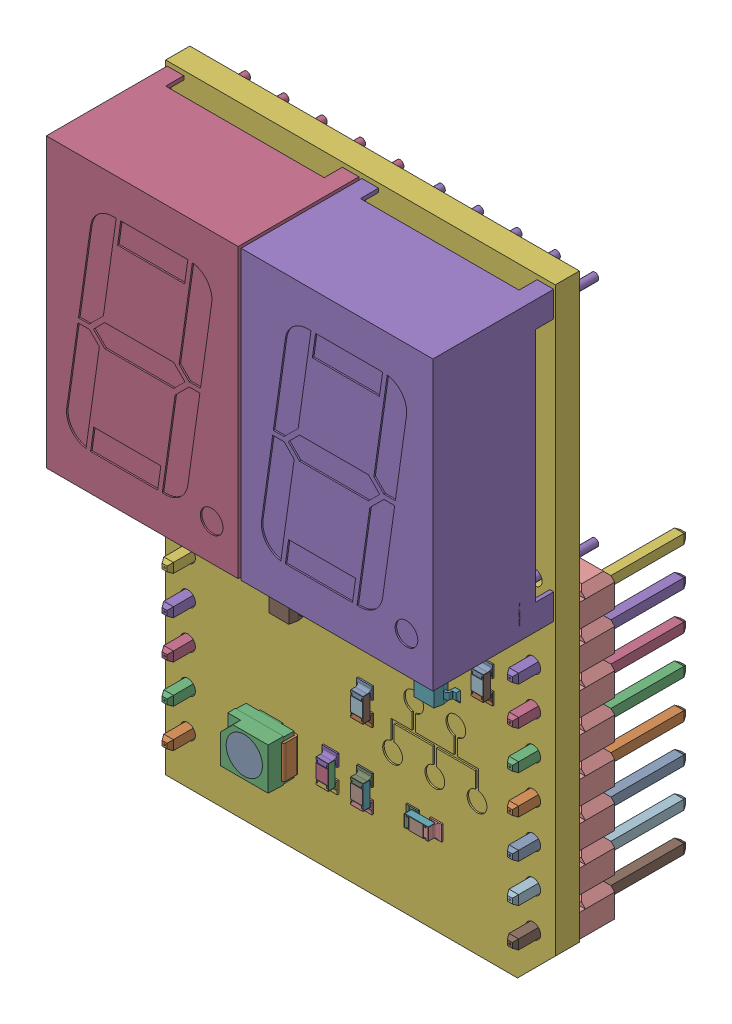
SolidWorks assembly 7_Seg_Click_Board, configuration Default. Lengths in mm.
Overall size (25.8 41 17.94).
119 component instances, 16 part files, 0 mates.
Components (placement in the parent):
- m20-9770842_asm.stp.1-1: m20-9770842_asm.stp.1 [Default] at (77.5496 46.3595 4.37) x (0 1 0) z (-1 0 0) size (20.32 11.48 2.54)
  - M20-977_ASM-1: M20-977_ASM [Default] at origin size (20.32 11.48 2.54)
    - M20-977-MOULD_2-1: M20-977-MOULD_2 [Default] at origin size (20.32 2.54 2.54)
    - M20-977-PIN.7-1: M20-977-PIN.7 [Default] at (2.54 -5.68 0) x (1 0 0) z (0 0 -1) size (0.64 11.48 0.64)
    - M20-977-PIN.7-2: M20-977-PIN.7 [Default] at (5.08 -5.68 0) x (1 0 0) z (0 0 -1) size (0.64 11.48 0.64)
    - M20-977-PIN.7-3: M20-977-PIN.7 [Default] at (7.62 -5.68 0) x (1 0 0) z (0 0 -1) size (0.64 11.48 0.64)
    - M20-977-PIN.7-4: M20-977-PIN.7 [Default] at (10.16 -5.68 0) x (1 0 0) z (0 0 -1) size (0.64 11.48 0.64)
    - M20-977-PIN.7-5: M20-977-PIN.7 [Default] at (12.7 -5.68 0) x (1 0 0) z (0 0 -1) size (0.64 11.48 0.64)
    - M20-977-PIN.7-6: M20-977-PIN.7 [Default] at (15.24 -5.68 0) x (1 0 0) z (0 0 -1) size (0.64 11.48 0.64)
    - M20-977-PIN.7-7: M20-977-PIN.7 [Default] at (17.78 -5.68 0) x (1 0 0) z (0 0 -1) size (0.64 11.48 0.64)
    - M20-977-PIN.7-8: M20-977-PIN.7 [Default] at (20.32 -5.68 0) x (1 0 0) z (0 0 -1) size (0.64 11.48 0.64)
- m20-9770842_asm.stp-1: m20-9770842_asm.stp [Default] at (100.4096 46.3595 4.37) x (0 1 0) z (-1 0 0) size (20.32 11.48 2.54)
  - M20-977_ASM_2-1: M20-977_ASM_2 [Default] at origin size (20.32 11.48 2.54)
    - M20-977-MOULD-1: M20-977-MOULD [Default] at origin size (20.32 2.54 2.54)
    - M20-977-PIN.5-1: M20-977-PIN.5 [Default] at (2.54 -5.68 0) x (1 0 0) z (0 0 -1) size (0.64 11.48 0.64)
    - M20-977-PIN.5-2: M20-977-PIN.5 [Default] at (5.08 -5.68 0) x (1 0 0) z (0 0 -1) size (0.64 11.48 0.64)
    - M20-977-PIN.5-3: M20-977-PIN.5 [Default] at (7.62 -5.68 0) x (1 0 0) z (0 0 -1) size (0.64 11.48 0.64)
    - M20-977-PIN.5-4: M20-977-PIN.5 [Default] at (10.16 -5.68 0) x (1 0 0) z (0 0 -1) size (0.64 11.48 0.64)
    - M20-977-PIN.5-5: M20-977-PIN.5 [Default] at (12.7 -5.68 0) x (1 0 0) z (0 0 -1) size (0.64 11.48 0.64)
    - M20-977-PIN.5-6: M20-977-PIN.5 [Default] at (15.24 -5.68 0) x (1 0 0) z (0 0 -1) size (0.64 11.48 0.64)
    - M20-977-PIN.5-7: M20-977-PIN.5 [Default] at (17.78 -5.68 0) x (1 0 0) z (0 0 -1) size (0.64 11.48 0.64)
    - M20-977-PIN.5-8: M20-977-PIN.5 [Default] at (20.32 -5.68 0) x (1 0 0) z (0 0 -1) size (0.64 11.48 0.64)
- arduino_uno_MLC0603.1.1.8-1: arduino_uno_MLC0603.1.1.8 [Default] at (93.2677 51.543 8.51) x (1 0 0) z (0 -1 0) size (2.36 0.6 1.03)
  - p4-1: p4 [Default] at origin size (1.55 0.45 0.8)
  - p3-1: p3 [Default] at origin size (1 0.03 0.8)
  - p2-1: p2 [Default] at origin size (0.8 0.6 1.03)
  - p1-1: p1 [Default] at origin size (0.8 0.6 1.03)
- User_Library-arduino_uno_ssot3.1.1-1: User_Library-arduino_uno_ssot3.1.1 [Default] at (84.6189 60.8527 8.41) x (0 1 0) z (1 0 0) size (3 1.13 3.09)
- Everlight_67-21SRC-TR8.STEP-1: Everlight_67-21SRC-TR8.STEP [Default] at (83.1478 51.2463 8.51) x (0 -1 0) z (-1 0 0) size (2.8 1.86 3.5)
  - User_Library-Everlight_67-21SRC-TR8-1: User_Library-Everlight_67-21SRC-TR8 [Default] at origin size (2.8 1.86 3.5)
    - User_Library-Everlight_67-21SRC-TR8_Imported_3-1: User_Library-Everlight_67-21SRC-TR8_Imported_3 [Default] at origin size (0.48 0.2 0.48)
    - User_Library-Everlight_67-21SRC-TR8_Imported_4-1: User_Library-Everlight_67-21SRC-TR8_Imported_4 [Default] at origin size (2.4 0.85 2.4)
    - User_Library-Everlight_67-21SRC-TR8_Imported-1: User_Library-Everlight_67-21SRC-TR8_Imported [Default] at origin size (2.2 1.01 3.5)
    - User_Library-Everlight_67-21SRC-TR8_Imported_2-1: User_Library-Everlight_67-21SRC-TR8_Imported_2 [Default] at origin size (2.8 1.8 3.2)
- Disp_SA56-11.1-1: Disp_SA56-11.1 [Default] at (77.4495 69.2194 8.4773) size (12.7 19.05 12)
  - SW3dPS-Disp_SA56-11-1: SW3dPS-Disp_SA56-11 [Default] at origin size (12.7 19.05 12)
    - SW3dPS-Disp_SA56-11_Open_CASCADE_STEP_translator_6.2_78.2-1: SW3dPS-Disp_SA56-11_Open_CASCADE_STEP_translator_6.2_78.2 [Default] at origin size (12.7 19.05 12)
      - SW3dPS-Disp_SA56-11_Disp_SA56-12_2-1: SW3dPS-Disp_SA56-11_Disp_SA56-12_2 [Default] at (5.0801 7.6201 8.0327) x (1 0 0) z (0 -1 0) size (12.7 12 19.05)
- Disp_SA56-11-1: Disp_SA56-11 [Default] at (90.3495 69.2194 8.4773) size (12.7 19.05 12)
  - SW3dPS-Disp_SA56-11_2-1: SW3dPS-Disp_SA56-11_2 [Default] at origin size (12.7 19.05 12)
    - SW3dPS-Disp_SA56-11_Open_CASCADE_STEP_translator_6.2_78.2_2-1: SW3dPS-Disp_SA56-11_Open_CASCADE_STEP_translator_6.2_78.2_2 [Default] at origin size (12.7 19.05 12)
      - SW3dPS-Disp_SA56-11_Disp_SA56-12-1: SW3dPS-Disp_SA56-11_Disp_SA56-12 [Default] at (5.0801 7.6201 8.0327) x (1 0 0) z (0 -1 0) size (12.7 12 19.05)
- 7_Seg_Click_Board-1: 7_Seg_Click_Board [Default] at (0 0.5 0) size (25.8 41 1.6)
- arduino_uno_MLC0603.1.1.8-2: arduino_uno_MLC0603.1.1.8 [Default] at (97.3056 65.7088 8.51) x (0 -1 0) z (-1 0 0) size (2.36 0.6 1.03)
  - p4-1: p4 [Default] at origin size (1.55 0.45 0.8)
  - p3-1: p3 [Default] at origin size (1 0.03 0.8)
  - p2-1: p2 [Default] at origin size (0.8 0.6 1.03)
  - p1-1: p1 [Default] at origin size (0.8 0.6 1.03)
- arduino_uno_MLC0603.1.1.8-3: arduino_uno_MLC0603.1.1.8 [Default] at (97.3056 61.7088 8.51) x (0 -1 0) z (-1 0 0) size (2.36 0.6 1.03)
  - p4-1: p4 [Default] at origin size (1.55 0.45 0.8)
  - p3-1: p3 [Default] at origin size (1 0.03 0.8)
  - p2-1: p2 [Default] at origin size (0.8 0.6 1.03)
  - p1-1: p1 [Default] at origin size (0.8 0.6 1.03)
- arduino_uno_MLC0603.1.1.8-4: arduino_uno_MLC0603.1.1.8 [Default] at (95.0056 65.7088 8.51) x (0 -1 0) z (-1 0 0) size (2.36 0.6 1.03)
  - p4-1: p4 [Default] at origin size (1.55 0.45 0.8)
  - p3-1: p3 [Default] at origin size (1 0.03 0.8)
  - p2-1: p2 [Default] at origin size (0.8 0.6 1.03)
  - p1-1: p1 [Default] at origin size (0.8 0.6 1.03)
- arduino_uno_MLC0603.1.1.8-5: arduino_uno_MLC0603.1.1.8 [Default] at (92.7056 65.7088 8.51) x (0 -1 0) z (-1 0 0) size (2.36 0.6 1.03)
  - p4-1: p4 [Default] at origin size (1.55 0.45 0.8)
  - p3-1: p3 [Default] at origin size (1 0.03 0.8)
  - p2-1: p2 [Default] at origin size (0.8 0.6 1.03)
  - p1-1: p1 [Default] at origin size (0.8 0.6 1.03)
- arduino_uno_MLC0603.1.1.8-6: arduino_uno_MLC0603.1.1.8 [Default] at (90.4056 65.7088 8.51) x (0 -1 0) z (-1 0 0) size (2.36 0.6 1.03)
  - p4-1: p4 [Default] at origin size (1.55 0.45 0.8)
  - p3-1: p3 [Default] at origin size (1 0.03 0.8)
  - p2-1: p2 [Default] at origin size (0.8 0.6 1.03)
  - p1-1: p1 [Default] at origin size (0.8 0.6 1.03)
- arduino_uno_MLC0603.1.1.8-7: arduino_uno_MLC0603.1.1.8 [Default] at (90.4056 61.7088 8.51) x (0 -1 0) z (-1 0 0) size (2.36 0.6 1.03)
  - p4-1: p4 [Default] at origin size (1.55 0.45 0.8)
  - p3-1: p3 [Default] at origin size (1 0.03 0.8)
  - p2-1: p2 [Default] at origin size (0.8 0.6 1.03)
  - p1-1: p1 [Default] at origin size (0.8 0.6 1.03)
- arduino_uno_MLC0603.1.1.8-8: arduino_uno_MLC0603.1.1.8 [Default] at (88.1056 65.7088 8.51) x (0 -1 0) z (-1 0 0) size (2.36 0.6 1.03)
  - p4-1: p4 [Default] at origin size (1.55 0.45 0.8)
  - p3-1: p3 [Default] at origin size (1 0.03 0.8)
  - p2-1: p2 [Default] at origin size (0.8 0.6 1.03)
  - p1-1: p1 [Default] at origin size (0.8 0.6 1.03)
- arduino_uno_MLC0603.1.1.8-9: arduino_uno_MLC0603.1.1.8 [Default] at (88.1056 61.7088 8.51) x (0 -1 0) z (-1 0 0) size (2.36 0.6 1.03)
  - p4-1: p4 [Default] at origin size (1.55 0.45 0.8)
  - p3-1: p3 [Default] at origin size (1 0.03 0.8)
  - p2-1: p2 [Default] at origin size (0.8 0.6 1.03)
  - p1-1: p1 [Default] at origin size (0.8 0.6 1.03)
- arduino_uno_MLC0603.1.1.8-10: arduino_uno_MLC0603.1.1.8 [Default] at (85.8056 65.7088 8.51) x (0 -1 0) z (-1 0 0) size (2.36 0.6 1.03)
  - p4-1: p4 [Default] at origin size (1.55 0.45 0.8)
  - p3-1: p3 [Default] at origin size (1 0.03 0.8)
  - p2-1: p2 [Default] at origin size (0.8 0.6 1.03)
  - p1-1: p1 [Default] at origin size (0.8 0.6 1.03)
- arduino_uno_MLC0603.1.1.8-11: arduino_uno_MLC0603.1.1.8 [Default] at (83.5056 65.7088 8.51) x (0 -1 0) z (-1 0 0) size (2.36 0.6 1.03)
  - p4-1: p4 [Default] at origin size (1.55 0.45 0.8)
  - p3-1: p3 [Default] at origin size (1 0.03 0.8)
  - p2-1: p2 [Default] at origin size (0.8 0.6 1.03)
  - p1-1: p1 [Default] at origin size (0.8 0.6 1.03)
- arduino_uno_MLC0603.1.1.8-12: arduino_uno_MLC0603.1.1.8 [Default] at (81.2056 65.7088 8.51) x (0 -1 0) z (-1 0 0) size (2.36 0.6 1.03)
  - p4-1: p4 [Default] at origin size (1.55 0.45 0.8)
  - p3-1: p3 [Default] at origin size (1 0.03 0.8)
  - p2-1: p2 [Default] at origin size (0.8 0.6 1.03)
  - p1-1: p1 [Default] at origin size (0.8 0.6 1.03)
- arduino_uno_MLC0603.1.1.8-13: arduino_uno_MLC0603.1.1.8 [Default] at (81.2056 61.7088 8.51) x (0 -1 0) z (-1 0 0) size (2.36 0.6 1.03)
  - p4-1: p4 [Default] at origin size (1.55 0.45 0.8)
  - p3-1: p3 [Default] at origin size (1 0.03 0.8)
  - p2-1: p2 [Default] at origin size (0.8 0.6 1.03)
  - p1-1: p1 [Default] at origin size (0.8 0.6 1.03)
- arduino_uno_MLC0603.1.1.8-14: arduino_uno_MLC0603.1.1.8 [Default] at (89.3331 51.4771 8.51) x (0 -1 0) z (-1 0 0) size (2.36 0.6 1.03)
  - p4-1: p4 [Default] at origin size (1.55 0.45 0.8)
  - p3-1: p3 [Default] at origin size (1 0.03 0.8)
  - p2-1: p2 [Default] at origin size (0.8 0.6 1.03)
  - p1-1: p1 [Default] at origin size (0.8 0.6 1.03)
- arduino_uno_MLC0603.1.1.8-15: arduino_uno_MLC0603.1.1.8 [Default] at (89.3331 56.4771 8.51) x (0 -1 0) z (-1 0 0) size (2.36 0.6 1.03)
  - p4-1: p4 [Default] at origin size (1.55 0.45 0.8)
  - p3-1: p3 [Default] at origin size (1 0.03 0.8)
  - p2-1: p2 [Default] at origin size (0.8 0.6 1.03)
  - p1-1: p1 [Default] at origin size (0.8 0.6 1.03)
- arduino_uno_MLC0603.1.1.8-16: arduino_uno_MLC0603.1.1.8 [Default] at (87.0331 51.4771 8.51) x (0 -1 0) z (-1 0 0) size (2.36 0.6 1.03)
  - p4-1: p4 [Default] at origin size (1.55 0.45 0.8)
  - p3-1: p3 [Default] at origin size (1 0.03 0.8)
  - p2-1: p2 [Default] at origin size (0.8 0.6 1.03)
  - p1-1: p1 [Default] at origin size (0.8 0.6 1.03)
- User_Library-arduino_uno_ssot3.1.1-2: User_Library-arduino_uno_ssot3.1.1 [Default] at (94.2189 60.8527 8.41) x (0 1 0) z (1 0 0) size (3 1.13 3.09)
